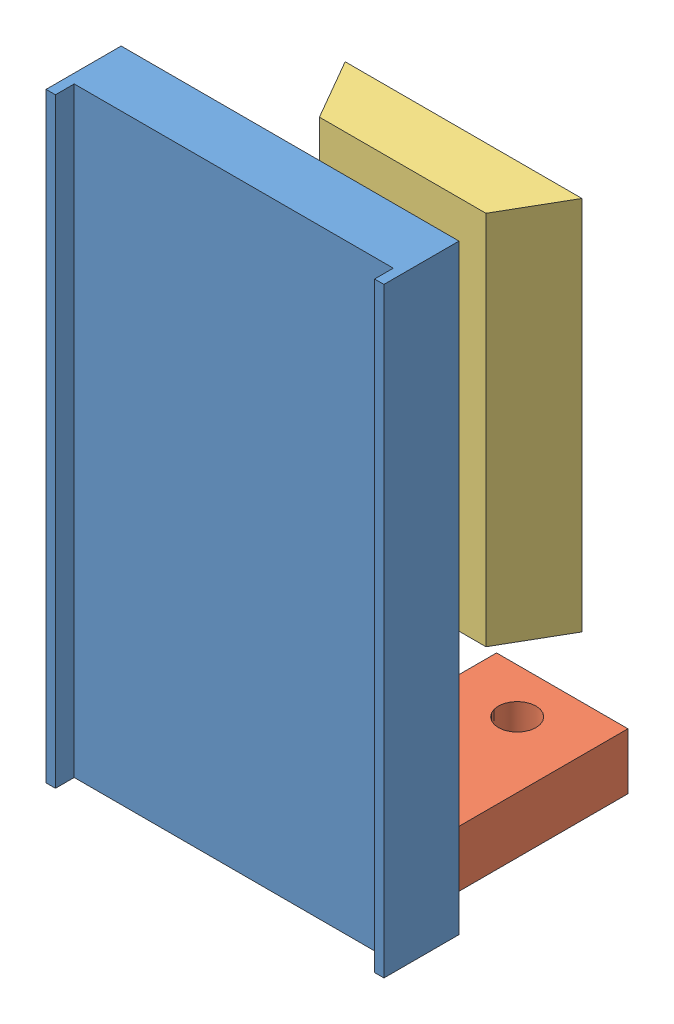
SolidWorks assembly nnx_64_holder, configuration Default. Lengths in mm.
Overall size (4.5 9 4.75).
3 component instances, 3 part files, 12 mates.
Components (placement in the parent):
- nnx_64_shaft-1: nnx_64_shaft [Default] at (-42.0361 20.4755 7.7711) size (4.5 8 1)
- leg_l-1: leg_l [Default] at (-42.0361 18.4755 6.7711) x (0 0 -1) z (1 0 0) size (3.75 6 1.75)
- slider_3mm5-1: slider_3mm5 [male] at (-42.0361 23.4755 6.3711) x (0 -1 0) z (-1 0 0) size (5 3.77 4.5)
Mates (geometry in assembly coordinates):
- Coincident1: coincident anti-aligned: plane of nnx_64_shaft-1 through (-42.0361 20.4755 7.7711) normal (0 0 -1); plane of littlel-1 through (-41.4111 21.2255 7.7711) normal (0 0 1)
- Coincident2: coincident anti-aligned: plane of nnx_64_shaft-1 through (-42.0361 20.4755 7.7711) normal (1 0 0); plane of littlel-1 through (-42.0361 21.2255 6.2354) normal (-1 0 0)
- Distance1: distance = 1 mm aligned: plane of littlel-1 through (-41.4111 15.4755 6.2354) normal (0 -1 0); plane of nnx_64_shaft-1 through (-42.0361 16.4755 8.5211) normal (0 -1 0)
- Coincident3: coincident anti-aligned: plane of nnx_64_shaft-1 through (-42.0361 20.4755 7.7711) normal (0 0 -1); plane of leg_l-1 through (-43.0361 18.4755 7.7711) normal (0 0 1)
- Coincident4: coincident aligned: plane of nnx_64_shaft-1 through (-42.0361 20.4755 7.7711) normal (1 0 0); plane of leg_l-1 through (-42.0361 18.4755 6.7711) normal (1 0 0)
- Distance3: distance = 1 mm aligned: plane of leg_l-1 through (-43.0361 15.4755 6.7711) normal (0 -1 0); plane of nnx_64_shaft-1 through (-42.0361 16.4755 8.5211) normal (0 -1 0)
- Coincident7: coincident anti-aligned: plane of leg_l-1 through (-43.0361 18.4755 6.2711) normal (0 0 -1); plane of slider-1 through (-42.2661 16.4755 6.5211) normal (0 0 1)
- Coincident8: coincident anti-aligned: plane of leg_l-1 through (-42.1611 18.4755 6.7711) normal (-1 0 0); plane of slider-1 through (-42.2661 21.4755 6.542) normal (1 0 0)
- Coincident9: coincident aligned: plane of leg_l-1 through (-43.0361 21.4755 6.7711) normal (0 1 0); plane of slider-1 through (-42.2661 21.4755 6.542) normal (0 1 0)
- Coincident10: coincident anti-aligned: plane of leg_l-1 through (-42.0361 18.4755 6.7711) normal (1 0 0); plane of slider_3mm5-1 through (-42.0361 23.4755 6.3711) normal (-1 0 0)
- Coincident11: coincident anti-aligned: plane of leg_l-1 through (-43.0361 18.4755 6.2711) normal (0 0 -1); plane of slider_3mm5-1 through (-40.9271 23.4765 6.2711) normal (0 0 1)
- Distance4: distance = 2 mm aligned: plane of leg_l-1 through (-43.0361 21.4755 6.7711) normal (0 1 0); plane of slider_3mm5-1 through (-42.0361 23.4755 6.3711) normal (0 1 0)
